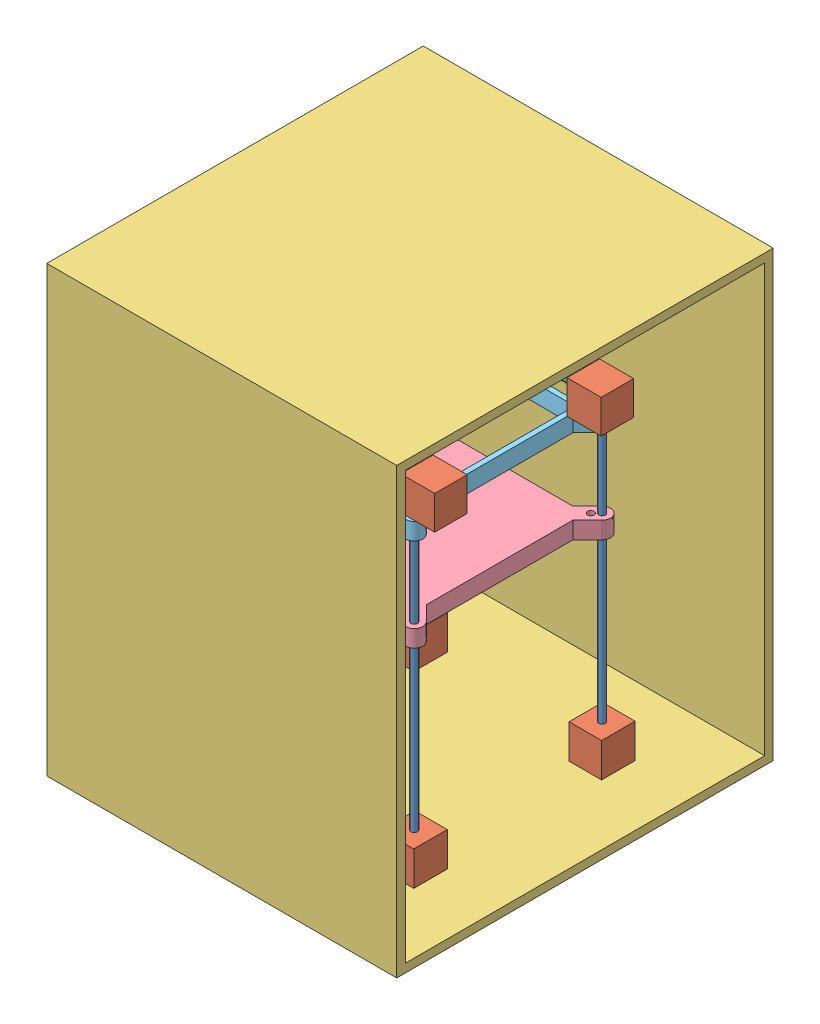
SolidWorks assembly ass1, configuration Default. Lengths in mm.
Overall size (410 520 441.05).
20 component instances, 9 part files, 37 mates.
Components (placement in the parent):
- vertical rod^ass1-1: vertical rod^ass1 [Default] at (-29.9588 108.6504 258.6204) x (-1 0 0) z (0 -1 0) size (7.59 7.59 340)
- motor-1: motor [Default] at (-29.9588 88.6504 258.6204) x (-1 0 0) z (0 -1 0) size (38.1 39.3 40)
- motor-2: motor [Default] at (190.0743 88.6504 38.5873) x (-1 0 0) z (0 -1 0) size (38.1 39.3 40)
- vertical rod^ass1-2: vertical rod^ass1 [Default] at (178.4347 108.6504 34.5316) x (-0.62143 0 0.783469) z (0 -1 0) size (7.59 7.59 340)
- outer case-1: outer case [Default] at (-29.9588 48.6504 258.6204) x (-1 0 0) z (0 -1 0) size (410 441.05 520)
- Part12-1: Part12 [Default] at (-29.9588 48.6504 369.1467) x (-1 0 0) z (0 0 -1)
- vertical rod^ass1-3: vertical rod^ass1 [Default] at (194.1553 108.6504 267.251) x (-0.772894 0 -0.634535) z (0 -1 0) size (7.59 7.59 340)
- vertical rod^ass1-4: vertical rod^ass1 [Default] at (-44.1228 108.6504 35.059) x (-0.46909 0 0.883151) z (0 -1 0) size (7.59 7.59 340)
- base-2: base [Default] at (-29.9588 279.9615 258.6204) size (240.03 20 240.03)
- top-2: top [Default] at (-29.9588 388.6504 258.6204) size (240.03 20 240.03)
- motor-3: motor [Default] at (170.0412 438.3157 265.6369) x (0 0 -1) z (1 0 0) size (38.1 39.3 40)
- motor-4: motor [Default] at (170.0412 438.3157 70.6369) x (0 0 -1) z (1 0 0) size (38.1 39.3 40)
- motor-5: motor [Default] at (190.0743 88.6504 258.5873) x (-1 0 0) z (0 -1 0) size (38.1 39.3 40)
- motor-6: motor [Default] at (-29.9257 88.6504 38.5873) x (-1 0 0) z (0 -1 0) size (38.1 39.3 40)
- motor-7: motor [Default] at (-29.9588 438.3157 245.6038) x (0 0 1) z (-1 0 0) size (38.1 39.3 40)
- motor-8: motor [Default] at (-29.9588 438.3157 50.6038) x (0 0 1) z (-1 0 0) size (38.1 39.3 40)
- Part4-1: Part4 [Default] at (190.0412 438.3157 70.6369) x (0 0 1) z (-1 0 0) size (7.59 7.59 240)
- Part4-2: Part4 [Default] at (190.0412 438.3157 265.6369) x (0 0 1) z (-1 0 0) size (7.59 7.59 240)
- topmoveable-1: topmoveable [Default] at (-29.9588 438.3157 245.6038) x (0 0 -1) z (1 0 0) size (233.1 50.07 50)
- Part8-1: Part8 [Default] at (5.0412 459.8105 223.6113) x (0 0 1) z (-1 0 0) size (79.82 61.58 20)
Mates (geometry in assembly coordinates):
- Coincident10: coincident aligned: plane of vertical rod^ass1-1 through (-39.9754 408.6504 268.6369) normal (0 1 0); plane of vertical rod^ass1-2 through (180.0577 408.6504 48.6038) normal (0 1 0)
- Coincident11: coincident aligned: circle of vertical rod^ass1-1; circle of motor-1
- Coincident12: coincident aligned: circle of motor-2; circle of vertical rod^ass1-2
- Parallel2: parallel anti-aligned: plane of motor-1 through (-20.9257 48.6504 258.6204) normal (1 0 0); plane of motor-2 through (161.008 48.6504 38.5873) normal (-1 0 0)
- InPlace3: in place: plane of motor-1 through (-29.9588 48.6504 258.6204) normal (0 -1 0); plane of ? through (0 48.6504 0) normal (0 -1 0); moOrthogonalPlaneRef_w of motor-1 through (-29.9588 48.6504 258.6204) normal (0 -1 0); unknown of ?; plane of motor-1 through (-29.9588 48.6504 258.6204) normal (0 -1 0); line of ? through (-55 0 48.6504) axis (0 -1 0); plane of motor-1 through (-29.9588 48.6504 258.6204) normal (0 -1 0); unknown of outer case-1
- Coincident15: coincident aligned: plane of motor-1; plane of outer case-1
- Coincident16: coincident aligned: moOrthogonalPlaneRef_w of motor-1 through (-29.9588 48.6504 258.6204) normal (0 0 -1); plane of outer case-1
- Coincident17: coincident anti-aligned: moOrthogonalPlaneRef_w of motor-1 through (-29.9588 48.6504 258.6204) normal (1 0 0); plane of outer case-1
- Coincident13: coincident aligned: plane of vertical rod^ass1-1 through (-39.9754 408.6504 268.6369) normal (0 1 0); plane of vertical rod^ass1-3 through (180.0577 408.6504 268.6369) normal (0 1 0)
- Coincident14: coincident aligned: plane of vertical rod^ass1-3 through (180.0577 408.6504 268.6369) normal (0 1 0); plane of vertical rod^ass1-4 through (-39.9754 408.6504 48.6038) normal (0 1 0)
- Concentric8: concentric aligned: cylinder of vertical rod^ass1-4 through (-39.9754 408.6504 48.6038) axis (0 -1 0) radius 3.7971; cylinder of base-2 through (-39.9754 348.2692 48.6038) axis (0 -1 0) radius 3.7971
- Concentric9: concentric aligned: cylinder of vertical rod^ass1-1 through (-39.9754 408.6504 268.6369) axis (0 -1 0) radius 3.7971; cylinder of base-2 through (-39.9754 348.2692 268.6369) axis (0 -1 0) radius 3.7971
- Concentric10: concentric aligned: cylinder of vertical rod^ass1-2 through (180.0577 408.6504 48.6038) axis (0 -1 0) radius 3.7971; cylinder of base-2 through (180.0577 348.2692 48.6038) axis (0 -1 0) radius 3.7971
- Concentric11: concentric aligned: cylinder of vertical rod^ass1-3 through (180.0577 408.6504 268.6369) axis (0 -1 0) radius 3.7971; cylinder of base-2 through (180.0577 348.2692 268.6369) axis (0 -1 0) radius 3.7971
- Parallel3: parallel aligned: plane of motor-1 through (-20.9257 48.6504 258.6204) normal (1 0 0); plane of motor-2 through (199.1074 48.6504 38.5873) normal (1 0 0)
- Parallel4: parallel aligned: plane of motor-1 through (-29.9588 48.6504 288.2857) normal (0 0 1); plane of motor-2 through (190.0743 48.6504 68.2526) normal (0 0 1)
- Parallel5: parallel anti-aligned: plane of motor-1 through (-29.9588 48.6504 248.9882) normal (0 0 -1); plane of motor-2 through (190.0743 48.6504 68.2526) normal (0 0 1)
- Parallel6: parallel aligned: plane of motor-2 through (190.0743 48.6504 68.2526) normal (0 0 1); plane of outer case-1 through (-29.9588 548.6504 -51.9059) normal (0 0 1)
- Parallel7: parallel aligned: plane of motor-2 through (199.1074 48.6504 38.5873) normal (1 0 0); plane of base-2 through (170.0412 299.9615 258.6204) normal (1 0 0)
- Concentric12: concentric aligned: cylinder of vertical rod^ass1-3 through (180.0577 408.6504 268.6369) axis (0 -1 0) radius 3.7971; cylinder of top-2 through (180.0577 398.6504 268.6369) axis (0 -1 0) radius 3.7971
- Coincident20: coincident aligned: plane of vertical rod^ass1-3 through (180.0577 408.6504 268.6369) normal (0 1 0); plane of top-2 through (-29.9588 408.6504 258.6204) normal (0 1 0)
- Concentric13: concentric aligned: cylinder of vertical rod^ass1-2 through (180.0577 408.6504 48.6038) axis (0 -1 0) radius 3.7971; cylinder of top-2 through (180.0577 398.6504 48.6038) axis (0 -1 0) radius 3.7971
- Coincident21: coincident anti-aligned: plane of top-2 through (-29.9588 408.6504 258.6204) normal (0 1 0); plane of motor-3 through (210.0412 408.6504 265.6369) normal (0 -1 0)
- Parallel10: parallel aligned: plane of top-2 through (-29.9588 408.6504 258.6204) normal (0 0 1); plane of motor-3 through (210.0412 438.3157 274.6701) normal (0 0 1)
- Width2: width aligned: plane of motor-3 through (210.0412 438.3157 274.6701) normal (0 0 1); plane of motor-3 through (210.0412 438.3157 236.5707) normal (0 0 -1); plane of top-2 through (-29.9588 408.6504 258.6204) normal (0 0 1); plane of top-2 through (-23.9588 408.6504 252.6204) normal (0 0 -1)
- Coincident28: coincident anti-aligned: plane of top-2 through (170.0412 408.6504 258.6204) normal (1 0 0); plane of motor-3 through (170.0412 438.3157 265.6369) normal (-1 0 0)
- InPlace5: in place: plane of motor-4 through (190.0412 438.3157 70.6369) normal (-1 0 0); plane of ? through (190.0412 0 0) normal (-1 0 0); plane of motor-4 through (190.0412 438.3157 70.6369) normal (-1 0 0); line of ? through (-55 190.0412 0) axis (0 0 1); plane of motor-4 through (190.0412 438.3157 70.6369) normal (-1 0 0); plane of ? through (190.0412 0 0) normal (0 0 1); plane of motor-4 through (190.0412 438.3157 70.6369) normal (-1 0 0); unknown of Part4-1
- Coincident32: coincident aligned: plane of motor-4; plane of Part4-1
- Coincident33: coincident aligned: moOrthogonalPlaneRef_w of motor-4 through (190.0412 438.3157 70.6369) normal (0 1 0); plane of Part4-1
- Coincident34: coincident anti-aligned: moOrthogonalPlaneRef_w of motor-4 through (190.0412 438.3157 70.6369) normal (0 0 -1); plane of Part4-1 through (190.0412 438.3157 70.6369) normal (0 0 1)
- Concentric16: concentric anti-aligned: cylinder of Part4-1 through (-60.6986 428.2992 60.6204) axis (1 0 0) radius 3.7971; cylinder of topmoveable-1 through (20.0412 428.2992 60.6204) axis (-1 0 0) radius 3.7971
- Concentric18: concentric anti-aligned: cylinder of Part4-2 through (-60.6986 428.2992 255.6204) axis (1 0 0) radius 3.7971; cylinder of topmoveable-1 through (20.0412 428.2992 255.6204) axis (-1 0 0) radius 3.7971
- LimitDistance1: limit distance = 191.3111 mm anti-aligned: plane of base-2 through (-29.9588 279.9615 258.6204) normal (0 -1 0); plane of motor-1 through (-29.9588 88.6504 258.6204) normal (0 1 0)
- LimitDistance2: limit distance = 150 mm anti-aligned: plane of topmoveable-1 through (20.0412 438.3157 245.6038) normal (1 0 0); plane of motor-3 through (170.0412 438.3157 265.6369) normal (-1 0 0)
- Width5: width anti-aligned: plane of Part8-1 through (5.0412 459.8105 223.6113) normal (1 0 0); plane of Part8-1 through (-14.9588 459.8105 223.6113) normal (-1 0 0); plane of topmoveable-1 through (-29.9588 438.3157 245.6038) normal (-1 0 0); plane of topmoveable-1 through (20.0412 438.3157 245.6038) normal (1 0 0)
- Concentric23: concentric anti-aligned: cylinder of topmoveable-1 through (-4.9588 454.7089 274.6701) axis (0 0 -1) radius 4.0011; cylinder of Part8-1 through (-4.9588 454.7089 124.8508) axis (0 0 1) radius 4
- LimitDistance3: limit distance = 50.7638 mm anti-aligned: plane of Part8-1 through (-14.9588 409.368 204.6674) normal (0 0 1); plane of topmoveable-1 through (9.1936 468.9664 255.4311) normal (0 0 -1)
